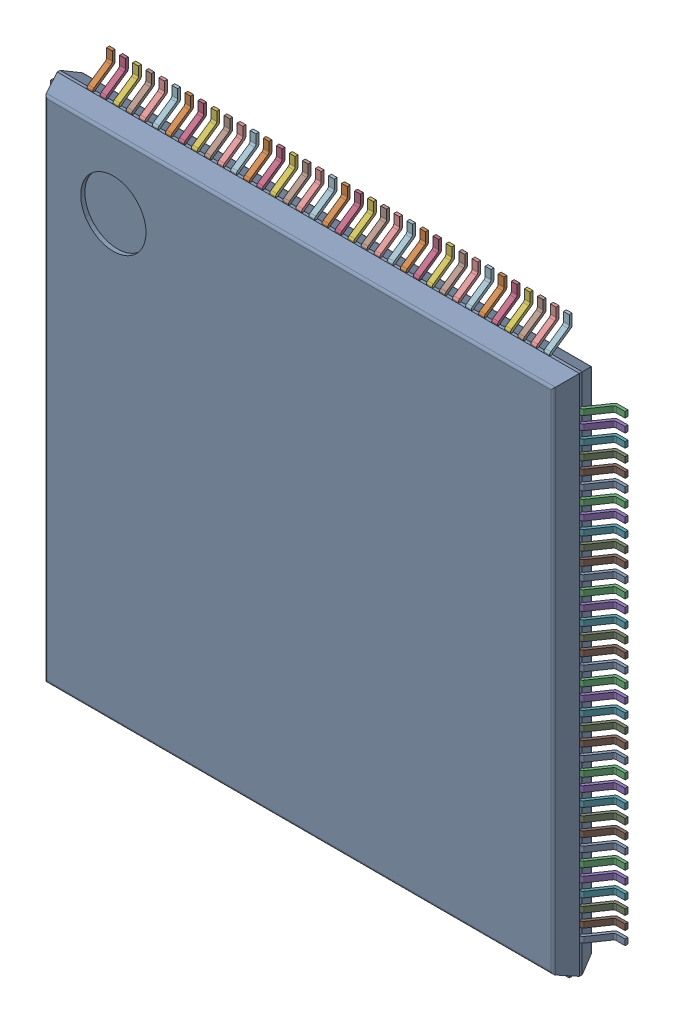
SolidWorks assembly IC2_1.step, configuration Default. Lengths in mm.
Overall size (22 22 1.6).
4 component instances, 3 part files, 0 mates.
Components (placement in the parent):
- 6348794688_1.step-3: 6348794688_1.step [Default] at (384.2997 276.4696 0) x (1 0 0) z (0 0 1) size (22 22 1.6)
  - Body-1211_1.step-5: Body-1211_1.step [Default] at origin size (20 20 1.5)
  - PinsArrayLR-1212_1.step-5: PinsArrayLR-1212_1.step [Default] at origin size (22 17.72 0.86)
  - PinsArrayTB_1.step-5: PinsArrayTB_1.step [Default] at origin size (17.72 22 0.86)
